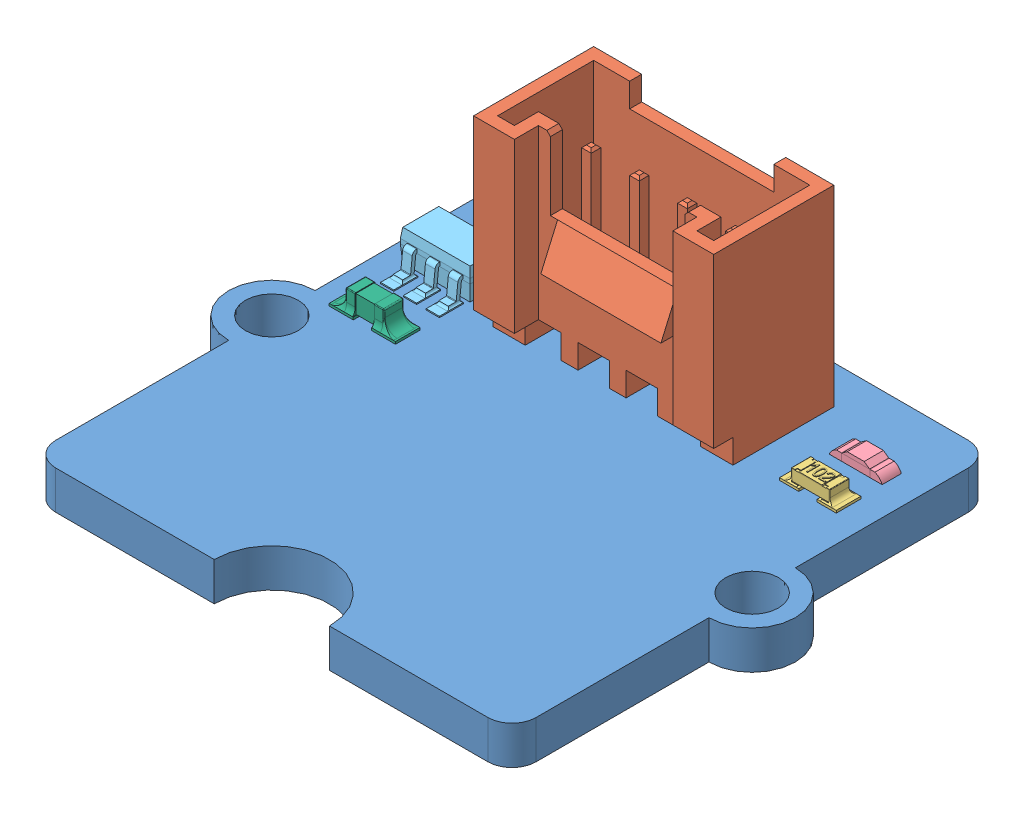
SolidWorks assembly Grove touch sensor, configuration Défaut. Lengths in mm.
Overall size (23.6 11 20).
7 component instances, 6 part files, 14 mates.
Components (placement in the parent):
- PCB grove 20x20 - Touch V1.1-1: PCB grove 20x20 - Touch V1.1 [Défaut] at (0.1376 -2.0005 -0.8069) x (0 0 1) z (-1 0 0) size (20 1.6 23.6)
- Connecteur Grove (droit)-1: Connecteur Grove (droit) [Défaut] at (0.1376 -0.4005 -4.2069) size (10 11 5)
- 603 resistor 102-1: 603 resistor 102 [Default] at (7.8373 -0.4005 -5.9397) size (2.36 0.62 1.03)
- led 0603-1: led 0603 [Default] at (7.8471 -0.4005 -7.8104) size (2.2 0.46 0.8)
- 603 resistor 102-2: 603 resistor 102 [Default] at (-7.6884 -0.4005 -9.5894) size (2.36 0.62 1.03)
- SOT23-6-1: SOT23-6 [Default] at (-7.5186 -0.4005 -6.0652) x (0 0 1) z (-1 0 0) size (3.7 1.4 2.9)
- 603 cap on pad-1: 603 cap on pad [Défaut] at (-7.6266 -0.4005 -2.8493) size (2.76 0.91 1.12)
Mates (geometry in assembly coordinates):
- Coïncidente3: coincident anti-aligned: plane of PCB grove 20x20 - Touch V1.1-1 through (0.1376 -0.4005 -0.8069) normal (0 1 0); plane of Connecteur Grove (droit)-1 through (0.1376 -0.4005 -4.2069) normal (0 -1 0)
- Distance2: distance = 1.6 mm aligned: plane of PCB grove 20x20 - Touch V1.1-1 through (0.1376 -0.4005 -10.8069) normal (0 0 -1); plane of Connecteur Grove (droit)-1 through (-4.8624 7.5995 -9.2069) normal (0 0 -1)
- Distance3: distance = 5 mm aligned: plane of Connecteur Grove (droit)-1 through (5.1376 7.5995 -9.2069) normal (1 0 0); plane of PCB grove 20x20 - Touch V1.1-1 through (10.1376 -0.4005 -0.8069) normal (1 0 0)
- Coïncidente4: coincident aligned: plane of 603 resistor 102-1 through (7.8373 -0.4005 -5.9397) normal (0 -1 0); plane of led 0603-1 through (8.9471 -0.4005 -7.4104) normal (0 -1 0)
- Coïncidente5: coincident aligned: plane of 603 resistor 102-1 through (7.8373 -0.4005 -5.9397) normal (0 -1 0); plane of 603 resistor 102-2 through (-7.6884 -0.4005 -9.5894) normal (0 -1 0)
- Coïncidente6: coincident: moEndPointRef_w of 603 resistor 102-2; plane of 603 cap on pad-1 through (-7.6266 -0.4005 -2.8493) normal (0 -1 0)
- Coïncidente7: coincident aligned: plane of 603 resistor 102-2 through (-7.6884 -0.4005 -9.5894) normal (0 -1 0); plane of SOT23-6-1 through (-7.5186 -0.4005 -6.0652) normal (0 -1 0)
- Coïncidente8: coincident anti-aligned: plane of PCB grove 20x20 - Touch V1.1-1 through (0.1376 -0.4005 -0.8069) normal (0 1 0); plane of 603 resistor 102-2 through (-7.6884 -0.4005 -9.5894) normal (0 -1 0)
- Parallèle1: parallel: plane of PCB grove 20x20 - Touch V1.1-1 through (-9.8624 -0.4005 -0.8069) normal (-1 0 0); line of SOT23-6-1 through (-6.1186 -0.3005 -6.8152) axis (0 0 1)
- Verrouiller3: lock: unknown of ?; unknown of ?
- Verrouiller4: lock: unknown of ?; unknown of ?
- Verrouiller5: lock: unknown of ?; unknown of ?
- Verrouiller6: lock: unknown of ?; unknown of ?
- Verrouiller7: lock: unknown of ?; unknown of ?
